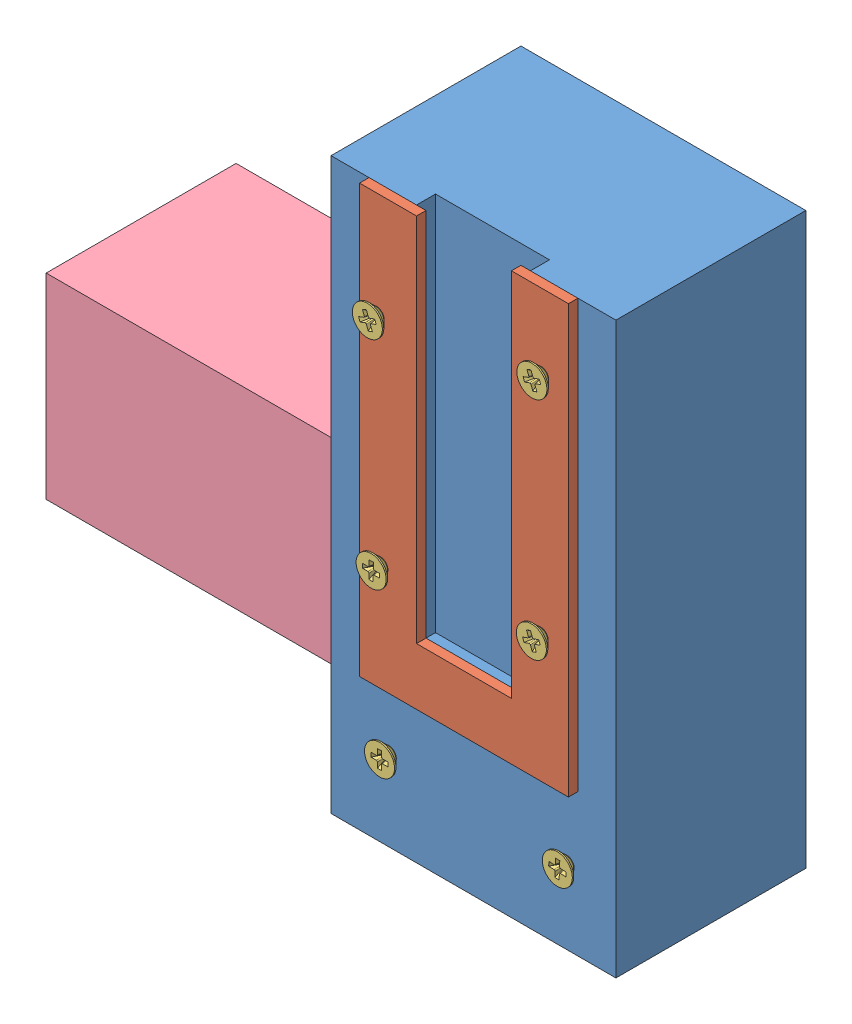
SolidWorks assembly Baugruppe3, configuration Standard. Lengths in mm.
Overall size (300 300 109.86).
9 component instances, 4 part files, 6 mates.
Components (placement in the parent):
- Klotz-1: Klotz [Standard] at (-46.587 -146.5388 350) size (150 300 100)
- Blecj-1: Blecj [Standard] at origin size (110 225 5)
- cross fh tapping 7976_din-2: cross fh tapping 7976_din [Tapping screw DIN 7982-ST8x50-C-H-S] at (-72.5838 -107.4347 354.86) x (0 0 -1) z (0.999235 -0.039107 0) size (50 15.8 15.8)
- cross fh tapping 7976_din-3: cross fh tapping 7976_din [Tapping screw DIN 7982-ST8x50-C-H-S] at (-167.6035 97.7078 359.86) x (0 0 -1) z (0.939173 0.343445 0) size (50 15.8 15.8)
- cross fh tapping 7976_din-4: cross fh tapping 7976_din [Tapping screw DIN 7982-ST8x50-C-H-S] at (-165.618 -15.4624 359.86) x (0 0 -1) z (0.999936 -0.011282 0) size (50 15.8 15.8)
- cross fh tapping 7976_din-5: cross fh tapping 7976_din [Tapping screw DIN 7982-ST8x50-C-H-S] at (-80.9695 113.6249 359.86) x (0 0 -1) z (0.939235 0.343274 0) size (50 15.8 15.8)
- cross fh tapping 7976_din-6: cross fh tapping 7976_din [Tapping screw DIN 7982-ST8x50-C-H-S] at (-81.2458 -5.3187 359.86) x (0 0 -1) z (0.942999 0.332796 0) size (50 15.8 15.8)
- cross fh tapping 7976_din-7: cross fh tapping 7976_din [Tapping screw DIN 7982-ST8x50-C-H-S] at (-166.2069 -104.3214 354.86) x (0 0 -1) z (0.999996 0.002649 0) size (50 15.8 15.8)
- Klotz-Breit-1: Klotz-Breit [Standard] at origin size (150 103.24 100)
Mates (geometry in assembly coordinates):
- Deckungsgleich1: coincident aligned: plane of Klotz-1 through (-46.587 153.4612 350) normal (0 0 1); circle of cross fh tapping 7976_din-7
- Deckungsgleich2: coincident aligned: plane of Blecj-1 through (0 0 355) normal (0 0 1); circle of cross fh tapping 7976_din-4
- Deckungsgleich3: coincident aligned: plane of Blecj-1 through (0 0 355) normal (0 0 1); circle of cross fh tapping 7976_din-3
- Deckungsgleich4: coincident aligned: plane of Blecj-1 through (0 0 355) normal (0 0 1); circle of cross fh tapping 7976_din-5
- Deckungsgleich5: coincident aligned: plane of Blecj-1 through (0 0 355) normal (0 0 1); circle of cross fh tapping 7976_din-6
- Deckungsgleich6: coincident aligned: plane of Klotz-1 through (-46.587 153.4612 350) normal (0 0 1); circle of cross fh tapping 7976_din-2
